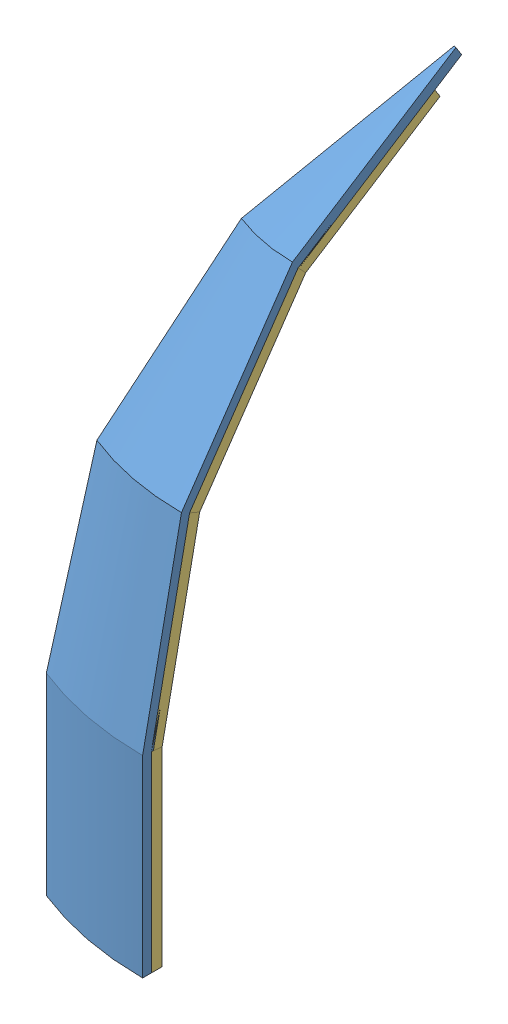
SolidWorks assembly Assem1, configuration Default. Lengths in mm.
Overall size (563.93 3015.97 1482.16).
3 component instances, 3 part files, 6 mates.
Components (placement in the parent):
- Part1-1: Part1 [Default] at (643.5811 535.4134 3088.0664) size (555.23 3015.97 1482.16)
- steel 1-1: steel 1 [Default] at (103.5995 535.4134 2992.4104) x (0.927184 0 0.374607) z (-0.374607 0 0.927184) size (50 2898.58 1340.95)
- steel 2-1: steel 2 [Default] at (643.5811 535.4134 3097.3722) x (0 0 -1) z (1 0 0) size (1340.95 2898.58 50)
Mates (geometry in assembly coordinates):
- Coincident3: coincident aligned: plane of Part1-1 through (643.5811 535.4134 1655.909) normal (0 -1 0); plane of steel 1-1 through (103.5995 535.4134 2992.4104) normal (0 -1 0)
- Tangent1: tangent anti-aligned: cone of Part1-1 through (643.5811 3031.0187 1655.909) axis (0 1 0); plane of steel 1-1 through (364.8722 3027.3484 2359.0851) normal (0.201276 -0.843391 -0.498176)
- Coincident5: coincident: plane of Part1-1 through (643.5811 535.4134 1655.909) normal (0 -1 0); plane of steel 2-1 through (737.4728 535.4134 3097.3722) normal (0 -1 0)
- Tangent2: tangent: cone of Part1-1 through (643.5811 3031.0187 1655.909) axis (0 1 0); plane of steel 2-1 through (732.4728 3027.3484 2412.2887) normal (0 -0.843391 -0.5373)
- Coincident7: coincident aligned: plane of Part1-1 through (146.1511 535.4134 2887.0916) normal (-0.927184 0 -0.374607); plane of steel 1-1 through (446.0219 2790.2101 2144.8853) normal (-0.927184 0 -0.374607)
- Coincident8: coincident aligned: plane of Part1-1 through (643.5811 535.4134 3088.0664) normal (1 0 0); plane of steel 2-1 through (643.5811 2790.2101 2183.287) normal (1 0 0)
